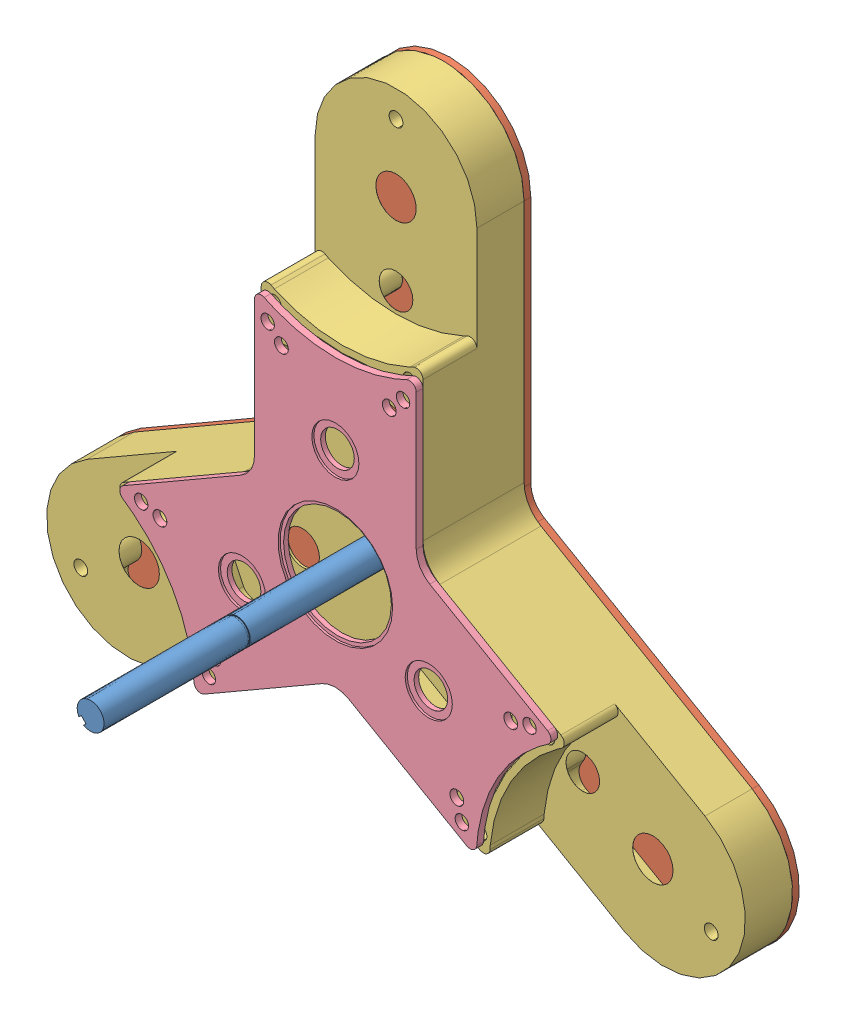
SolidWorks assembly Tri Wheel Assembly, configuration Default. Lengths in mm.
Overall size (420.3 432.7 177.8).
4 component instances, 4 part files, 13 mates.
Components (placement in the parent):
- Shaft A-1: Shaft A [Default] at (150.1683 -188.7686 -169.991) x (-0.715595 -0.698516 0) z (0.698516 -0.715595 0) size (12.7 177.8 12.7)
- Carrier_Drive Plate-1: Carrier_Drive Plate [Default] at (150.1683 -188.7686 -339.2566) x (1 0 0) z (0 -1 0) size (329.17 3.17 295.28)
- Main Casing-1: Main Casing [Default] at (150.1683 -188.7686 -313.8566) x (0.5 -0.866025 0) z (0.866025 0.5 0) size (329.17 47.62 295.28)
- Carrier_tumble-1: Carrier_tumble [Default] at (150.1683 -188.7686 -288.4566) size (203.15 176.79 3.21)
Mates (geometry in assembly coordinates):
- Coincident1: coincident anti-aligned: circle of ?; circle of Shaft A-1
- Concentric17: concentric aligned: circle of ?; circle of Shaft A-1
- Concentric38: concentric anti-aligned: circle of ?; cylinder of Carrier_Drive Plate-1 through (150.1683 -188.7686 -339.2566) axis (0 0 1) radius 17.4625
- Distance11: distance = 0.9906 mm anti-aligned: plane of ? through (150.1683 -188.7686 -335.091) normal (0 0 -1); plane of Carrier_Drive Plate-1 through (150.1683 -188.7686 -336.0816) normal (0 0 1)
- Concentric42: concentric anti-aligned: circle of ?; circle of Carrier_Drive Plate-1
- Concentric47: concentric aligned: circle of ?; circle of Carrier_Drive Plate-1
- Concentric56: concentric anti-aligned: circle of ?; circle of Main Casing-1
- Coincident14: coincident anti-aligned: plane of Carrier_Drive Plate-1 through (150.1683 -188.7686 -336.0816) normal (0 0 1); plane of Main Casing-1 through (23.6853 -261.7936 -336.0816) normal (0 0 -1)
- Concentric58: concentric aligned: cylinder of Shaft A-1 through (150.1683 -188.7686 -347.791) axis (0 0 1) radius 6.35; cylinder of ? through (150.1683 -188.7686 -376.366) axis (0 0 1) radius 7.9375
- Distance21: distance = 0.9906 mm anti-aligned: plane of ? through (150.1683 -188.7686 -312.866) normal (0 0 -1); plane of Main Casing-1 through (236.4537 -209.2561 -313.8566) normal (0 0 1)
- Distance22: distance = 0.9906 mm anti-aligned: plane of ? through (106.1743 -214.1686 -312.866) normal (0 0 -1); plane of Main Casing-1 through (236.4537 -209.2561 -313.8566) normal (0 0 1)
- GearMate15: gear = 914.4 : 508 mm: circle of ?; circle of ?
- Coincident19: coincident anti-aligned: plane of Main Casing-1 through (150.1683 -188.7686 -288.4566) normal (0 0 1); plane of Carrier_tumble-1 through (150.1683 -24.0568 -288.4566) normal (0 0 -1)
